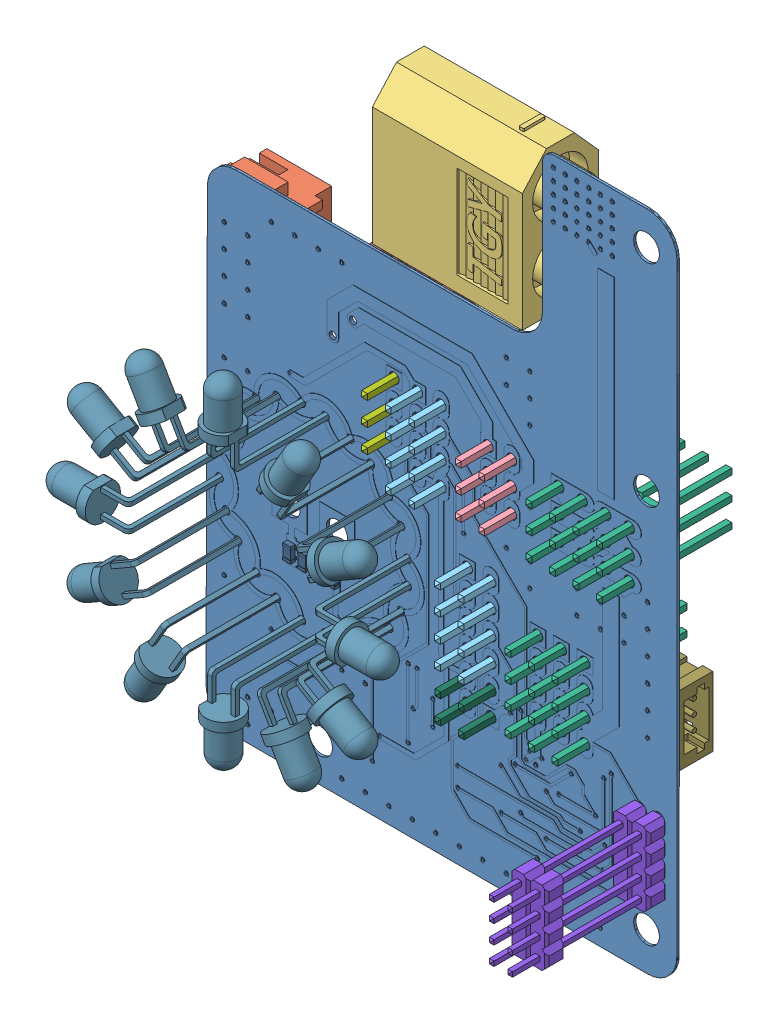
SolidWorks assembly pcb_distribution, configuration Default. Lengths in mm.
Overall size (57.82 71.9 27.2).
142 component instances, 19 part files, 0 mates.
Components (placement in the parent):
- Dip_distribution-1: Dip_distribution [Default] at origin size (51.25 71.9 0.34)
- S4B-XH-SM4-TB_distribution-1: S4B-XH-SM4-TB_distribution [Default] at (-4.2836 19.4855 0) x (0 1 0) z (-1 0 0) size (14.95 6 10)
- XT-60_distribution-1: XT-60_distribution [Default] at (18.1546 68.4711 30.4784) x (0 1 0) z (-1 0 0) size (16.3 8.2 21.2)
- 2x3_male_2.54x254_distribution-1: 2x3_male_2.54x254_distribution [Default] at (23.4683 11.0972 -0.0184) x (-1 0 0) z (0 -1 0) size (5.08 14.48 7.62)
- 2x4_male_2.54x254_distribution-1: 2x4_male_2.54x254_distribution [Default] at (13.354 17.4711 -0.0063) x (1 0 0) z (0 1 0) size (5.08 14.48 10.16)
- 2x4_male_2.54x254_distribution-2: 2x4_male_2.54x254_distribution [Default] at (21.2411 -3.9486 -0.0039) x (-1 0 0) z (0 -1 0) size (5.08 14.48 10.16)
- 3x4_male_2.54x254_distribution-3: 3x4_male_2.54x254_distribution [Default] at (26.2659 1.164 -0.0197) x (1 0 0) z (0 1 0) size (7.62 14.48 10.16)
- 3x4_male_2.54x254_distribution-6: 3x4_male_2.54x254_distribution [Default] at (28.5455 11.1175 -0.0174) x (0 1 0) z (-1 0 0) size (7.62 14.48 10.16)
- 1x3_male_2.54x254_distribution-1: 1x3_male_2.54x254_distribution [Default] at (10.8154 17.4747 -0.0262) x (0 -1 0) z (1 0 0) size (7.62 14.48 2.54)
- 2x4_male_2.0x2.0_distribution-1: 2x4_male_2.0x2.0_distribution [Default] at (39.2368 -9.9978 0.322) x (-1 0 0) z (0 1 0) size (4 18.21 8)
- 6444562_6444562_distribution-1: 6444562_6444562_distribution [Default] at (2.057 0 0.322)
- SOT 23_distribution-1: SOT 23_distribution [Default] at (20.6403 -14.1079 -0.55) x (-1 0 0) z (0 -1 0) size (3 1.1 2.5)
- SOT 23_distribution-2: SOT 23_distribution [Default] at (25.4006 -18.5273 -0.55) x (-1 0 0) z (0 -1 0) size (3 1.1 2.5)
- SOT 23_distribution-3: SOT 23_distribution [Default] at (15.8994 -18.4438 -0.55) x (-1 0 0) z (0 -1 0) size (3 1.1 2.5)
- SOT 23_distribution-4: SOT 23_distribution [Default] at (20.6481 -18.5304 -0.55) x (-1 0 0) z (0 -1 0) size (3 1.1 2.5)
- SOT 23_distribution-5: SOT 23_distribution [Default] at (15.873 -14.4885 -0.55) x (1 0 0) z (0 1 0) size (3 1.1 2.5)
- SOT 23_distribution-6: SOT 23_distribution [Default] at (25.3777 -14.0832 -0.55) x (-1 0 0) z (0 -1 0) size (3 1.1 2.5)
- Resistor 0603_distribution-1: Resistor 0603_distribution [Default] at (4.439 -4.231 0.352) x (0 1 0) z (1 0 0) size (1.6 0.51 0.86)
- Resistor 0603_distribution-2: Resistor 0603_distribution [Default] at (2.851 -4.231 0.352) x (0 1 0) z (1 0 0) size (1.6 0.51 0.86)
- Resistor 0603_distribution-3: Resistor 0603_distribution [Default] at (-0.324 -4.231 0.352) x (0 1 0) z (1 0 0) size (1.6 0.51 0.86)
- Resistor 0603_distribution-4: Resistor 0603_distribution [Default] at (1.264 -4.231 0.352) x (0 1 0) z (1 0 0) size (1.6 0.51 0.86)
- Resistor 0603_distribution-5: Resistor 0603_distribution [Default] at (12.065 -18.63 -0.03) x (0 -1 0) z (1 0 0) size (1.6 0.51 0.86)
- Resistor 0603_distribution-6: Resistor 0603_distribution [Default] at (9.208 -18.676 -0.03) x (0 1 0) z (-1 0 0) size (1.6 0.51 0.86)
- 4xRes_0402_distribution-1: 4xRes_0402_distribution [По умолчанию] at (31.8213 -10.0502 0) x (0 -1 0) z (1 0 0) size (2 0.37 1)
- 4xRes_0402_distribution-2: 4xRes_0402_distribution [По умолчанию] at (31.9306 -14.0825 0) x (0 1 0) z (-1 0 0) size (2 0.37 1)
- 4xRes_0402_distribution-3: 4xRes_0402_distribution [По умолчанию] at (31.9792 -18.2304 0) x (0 -1 0) z (1 0 0) size (2 0.37 1)
- S3B-ZR-SM4A-TF_distribution-1: S3B-ZR-SM4A-TF_distribution [Default] at (35.1671 -0.5265 0) x (0 -1 0) z (1 0 0) size (7.5 3.7 6.5)
- S3B-ZR-SM4A-TF_distribution-2: S3B-ZR-SM4A-TF_distribution [Default] at (-2.9698 -16.67 0) x (0 1 0) z (-1 0 0) size (7.5 3.7 6.5)
- S4B-ZR-SM4A-TF_distribution-1: S4B-ZR-SM4A-TF_distribution [Default] at (11.43 21.5177 0) x (1 0 0) z (0 1 0) size (9 3.7 6.5)
- LED DIP 3MM_distribution-1: LED DIP 3MM_distribution [Default] at (2.075 -11.8811 10.0396) x (0 0 1) z (0 -1 0) size (12.12 3.5 8.5)
- LED DIP 3MM_distribution-2: LED DIP 3MM_distribution [Default] at (12.389 5.9188 10.16) x (0 0 1) z (0.866025 0.5 0) size (12.12 3.5 8.5)
- LED DIP 3MM_distribution-3: LED DIP 3MM_distribution [Default] at (8.0206 10.3285 10.1335) x (0 0 1) z (0.5 0.866025 0) size (12.12 3.5 8.5)
- LED DIP 3MM_distribution-4: LED DIP 3MM_distribution [Default] at (8.0314 -10.3333 10.013) x (0 0 1) z (0.5 -0.866025 0) size (12.12 3.5 8.5)
- LED DIP 3MM_distribution-5: LED DIP 3MM_distribution [Default] at (-9.8416 -0.0229 10.1633) x (0 0 1) z (-1 0 0) size (12.12 3.5 8.5)
- LED DIP 3MM_distribution-6: LED DIP 3MM_distribution [Default] at (2.0728 11.943 10.1055) x (0 0 1) z (0 1 0) size (12.12 3.5 8.5)
- LED DIP 3MM_distribution-7: LED DIP 3MM_distribution [Default] at (12.4022 -5.9974 10.1382) x (0 0 1) z (0.866025 -0.5 0) size (12.12 3.5 8.5)
- LED DIP 3MM_distribution-8: LED DIP 3MM_distribution [Default] at (-8.2867 -5.9857 10.1382) x (0 0 1) z (-0.866025 -0.5 0) size (12.12 3.5 8.5)
- LED DIP 3MM_distribution-9: LED DIP 3MM_distribution [Default] at (-3.8923 10.3362 10.1121) x (0 0 1) z (-0.5 0.866025 0) size (12.12 3.5 8.5)
- LED DIP 3MM_distribution-10: LED DIP 3MM_distribution [Default] at (13.973 0.0173 10.0631) x (0 0 1) z (1 0 0) size (12.12 3.5 8.5)
- LED DIP 3MM_distribution-11: LED DIP 3MM_distribution [Default] at (-3.8857 -10.3081 10.1883) x (0 0 1) z (-0.5 -0.866025 0) size (12.12 3.5 8.5)
- LED DIP 3MM_distribution-12: LED DIP 3MM_distribution [Default] at (-8.2285 5.9806 10.1674) x (0 0 1) z (-0.866025 0.5 0) size (12.12 3.5 8.5)
- 2x2_male_2.54x254_distribution-1: 2x2_male_2.54x254_distribution [Default] at (21.251 -6.496 -0.0202) x (0 -1 0) z (1 0 0) size (5.08 14.48 5.08)
- Static_Via_Static_Via_distribution-1: Static_Via_Static_Via_distribution [Default] at (27.94 45.72 0.322)
- Static_Via_Static_Via_distribution-2: Static_Via_Static_Via_distribution [Default] at (29.21 45.72 0.322)
- Static_Via_Static_Via_distribution-3: Static_Via_Static_Via_distribution [Default] at (30.48 45.72 0.322)
- Static_Via_Static_Via_distribution-4: Static_Via_Static_Via_distribution [Default] at (31.75 45.72 0.322)
- Static_Via_Static_Via_distribution-5: Static_Via_Static_Via_distribution [Default] at (33.02 45.72 0.322)
- Static_Via_Static_Via_distribution-6: Static_Via_Static_Via_distribution [Default] at (34.29 45.72 0.322)
- Static_Via_Static_Via_distribution-7: Static_Via_Static_Via_distribution [Default] at (34.29 44.45 0.322)
- Static_Via_Static_Via_distribution-8: Static_Via_Static_Via_distribution [Default] at (33.02 44.45 0.322)
- Static_Via_Static_Via_distribution-9: Static_Via_Static_Via_distribution [Default] at (31.75 44.45 0.322)
- Static_Via_Static_Via_distribution-10: Static_Via_Static_Via_distribution [Default] at (30.48 44.45 0.322)
- Static_Via_Static_Via_distribution-11: Static_Via_Static_Via_distribution [Default] at (29.21 44.45 0.322)
- Static_Via_Static_Via_distribution-12: Static_Via_Static_Via_distribution [Default] at (27.94 44.45 0.322)
- Static_Via_Static_Via_distribution-13: Static_Via_Static_Via_distribution [Default] at (27.94 43.18 0.322)
- Static_Via_Static_Via_distribution-14: Static_Via_Static_Via_distribution [Default] at (29.21 43.18 0.322)
- Static_Via_Static_Via_distribution-15: Static_Via_Static_Via_distribution [Default] at (30.48 43.18 0.322)
- Static_Via_Static_Via_distribution-16: Static_Via_Static_Via_distribution [Default] at (31.75 43.18 0.322)
- Static_Via_Static_Via_distribution-17: Static_Via_Static_Via_distribution [Default] at (33.02 43.18 0.322)
- Static_Via_Static_Via_distribution-18: Static_Via_Static_Via_distribution [Default] at (34.29 43.18 0.322)
- Static_Via_Static_Via_distribution-19: Static_Via_Static_Via_distribution [Default] at (34.29 41.91 0.322)
- Static_Via_Static_Via_distribution-20: Static_Via_Static_Via_distribution [Default] at (33.02 41.91 0.322)
- Static_Via_Static_Via_distribution-21: Static_Via_Static_Via_distribution [Default] at (31.75 41.91 0.322)
- Static_Via_Static_Via_distribution-22: Static_Via_Static_Via_distribution [Default] at (30.48 41.91 0.322)
- Static_Via_Static_Via_distribution-23: Static_Via_Static_Via_distribution [Default] at (29.21 41.91 0.322)
- Static_Via_Static_Via_distribution-24: Static_Via_Static_Via_distribution [Default] at (27.94 41.91 0.322)
- Static_Via_Static_Via_distribution-25: Static_Via_Static_Via_distribution [Default] at (27.94 40.64 0.322)
- Static_Via_Static_Via_distribution-26: Static_Via_Static_Via_distribution [Default] at (29.21 40.64 0.322)
- Static_Via_Static_Via_distribution-27: Static_Via_Static_Via_distribution [Default] at (30.48 40.64 0.322)
- Static_Via_Static_Via_distribution-28: Static_Via_Static_Via_distribution [Default] at (31.75 40.64 0.322)
- Static_Via_Static_Via_distribution-29: Static_Via_Static_Via_distribution [Default] at (33.02 40.64 0.322)
- Static_Via_Static_Via_distribution-30: Static_Via_Static_Via_distribution [Default] at (34.29 40.64 0.322)
- Static_Via_Static_Via_distribution-31: Static_Via_Static_Via_distribution [Default] at (-7.62 -7.62 0.322)
- Static_Via_Static_Via_distribution-32: Static_Via_Static_Via_distribution [Default] at (-7.62 -10.16 0.322)
- Static_Via_Static_Via_distribution-33: Static_Via_Static_Via_distribution [Default] at (-5.08 -12.7 0.322)
- Static_Via_Static_Via_distribution-34: Static_Via_Static_Via_distribution [Default] at (-2.54 -12.7 0.322)
- Static_Via_Static_Via_distribution-35: Static_Via_Static_Via_distribution [Default] at (-5.08 -20.32 0.322)
- Static_Via_Static_Via_distribution-36: Static_Via_Static_Via_distribution [Default] at (-2.54 -20.32 0.322)
- Static_Via_Static_Via_distribution-37: Static_Via_Static_Via_distribution [Default] at (-5.08 -22.86 0.322)
- Static_Via_Static_Via_distribution-38: Static_Via_Static_Via_distribution [Default] at (-2.54 -22.86 0.322)
- Static_Via_Static_Via_distribution-39: Static_Via_Static_Via_distribution [Default] at (7.62 -12.7 0.322)
- Static_Via_Static_Via_distribution-40: Static_Via_Static_Via_distribution [Default] at (5.08 -12.7 0.322)
- Static_Via_Static_Via_distribution-41: Static_Via_Static_Via_distribution [Default] at (5.08 -17.78 0.322)
- Static_Via_Static_Via_distribution-42: Static_Via_Static_Via_distribution [Default] at (7.62 -17.78 0.322)
- Static_Via_Static_Via_distribution-43: Static_Via_Static_Via_distribution [Default] at (5.08 -22.86 0.322)
- Static_Via_Static_Via_distribution-44: Static_Via_Static_Via_distribution [Default] at (7.62 -22.86 0.322)
- Static_Via_Static_Via_distribution-45: Static_Via_Static_Via_distribution [Default] at (10.16 -22.86 0.322)
- Static_Via_Static_Via_distribution-46: Static_Via_Static_Via_distribution [Default] at (12.7 -22.86 0.322)
- Static_Via_Static_Via_distribution-47: Static_Via_Static_Via_distribution [Default] at (15.24 -22.86 0.322)
- Static_Via_Static_Via_distribution-48: Static_Via_Static_Via_distribution [Default] at (17.78 -22.86 0.322)
- Static_Via_Static_Via_distribution-49: Static_Via_Static_Via_distribution [Default] at (20.32 -22.86 0.322)
- Static_Via_Static_Via_distribution-50: Static_Via_Static_Via_distribution [Default] at (22.86 -22.86 0.322)
- Static_Via_Static_Via_distribution-51: Static_Via_Static_Via_distribution [Default] at (25.4 -22.86 0.322)
- Static_Via_Static_Via_distribution-52: Static_Via_Static_Via_distribution [Default] at (27.94 -22.86 0.322)
- Static_Via_Static_Via_distribution-53: Static_Via_Static_Via_distribution [Default] at (30.48 -22.86 0.322)
- Static_Via_Static_Via_distribution-54: Static_Via_Static_Via_distribution [Default] at (33.02 -22.86 0.322)
- Static_Via_Static_Via_distribution-55: Static_Via_Static_Via_distribution [Default] at (26.67 -10.16 0.322)
- Static_Via_Static_Via_distribution-56: Static_Via_Static_Via_distribution [Default] at (25.4 -10.16 0.322)
- Static_Via_Static_Via_distribution-57: Static_Via_Static_Via_distribution [Default] at (26.035 -11.112 0.322)
- Static_Via_Static_Via_distribution-58: Static_Via_Static_Via_distribution [Default] at (38.1 -2.54 0.322)
- Static_Via_Static_Via_distribution-59: Static_Via_Static_Via_distribution [Default] at (38.1 0 0.322)
- Static_Via_Static_Via_distribution-60: Static_Via_Static_Via_distribution [Default] at (38.1 2.54 0.322)
- Static_Via_Static_Via_distribution-61: Static_Via_Static_Via_distribution [Default] at (38.1 5.08 0.322)
- Static_Via_Static_Via_distribution-62: Static_Via_Static_Via_distribution [Default] at (38.1 7.62 0.322)
- Static_Via_Static_Via_distribution-63: Static_Via_Static_Via_distribution [Default] at (38.1 10.16 0.322)
- Static_Via_Static_Via_distribution-64: Static_Via_Static_Via_distribution [Default] at (35.56 7.62 0.322)
- Static_Via_Static_Via_distribution-65: Static_Via_Static_Via_distribution [Default] at (33.02 7.62 0.322)
- Static_Via_Static_Via_distribution-66: Static_Via_Static_Via_distribution [Default] at (30.48 7.62 0.322)
- Static_Via_Static_Via_distribution-67: Static_Via_Static_Via_distribution [Default] at (35.56 5.08 0.322)
- Static_Via_Static_Via_distribution-68: Static_Via_Static_Via_distribution [Default] at (33.02 5.08 0.322)
- Static_Via_Static_Via_distribution-69: Static_Via_Static_Via_distribution [Default] at (30.48 5.08 0.322)
- Static_Via_Static_Via_distribution-70: Static_Via_Static_Via_distribution [Default] at (25.4 7.62 0.322)
- Static_Via_Static_Via_distribution-71: Static_Via_Static_Via_distribution [Default] at (25.4 5.08 0.322)
- Static_Via_Static_Via_distribution-72: Static_Via_Static_Via_distribution [Default] at (22.86 7.62 0.322)
- Static_Via_Static_Via_distribution-73: Static_Via_Static_Via_distribution [Default] at (25.4 12.7 0.322)
- Static_Via_Static_Via_distribution-74: Static_Via_Static_Via_distribution [Default] at (25.4 20.32 0.322)
- Static_Via_Static_Via_distribution-75: Static_Via_Static_Via_distribution [Default] at (25.4 22.86 0.322)
- Static_Via_Static_Via_distribution-76: Static_Via_Static_Via_distribution [Default] at (25.4 25.4 0.322)
- Static_Via_Static_Via_distribution-77: Static_Via_Static_Via_distribution [Default] at (22.86 25.4 0.322)
- Static_Via_Static_Via_distribution-78: Static_Via_Static_Via_distribution [Default] at (22.86 22.86 0.322)
- Static_Via_Static_Via_distribution-79: Static_Via_Static_Via_distribution [Default] at (5.08 25.4 0.322)
- Static_Via_Static_Via_distribution-80: Static_Via_Static_Via_distribution [Default] at (2.54 25.4 0.322)
- Static_Via_Static_Via_distribution-81: Static_Via_Static_Via_distribution [Default] at (0 25.4 0.322)
- Static_Via_Static_Via_distribution-82: Static_Via_Static_Via_distribution [Default] at (-7.62 22.86 0.322)
- Static_Via_Static_Via_distribution-83: Static_Via_Static_Via_distribution [Default] at (-5.08 22.86 0.322)
- Static_Via_Static_Via_distribution-84: Static_Via_Static_Via_distribution [Default] at (-5.08 20.32 0.322)
- Static_Via_Static_Via_distribution-85: Static_Via_Static_Via_distribution [Default] at (-7.62 20.32 0.322)
- Static_Via_Static_Via_distribution-86: Static_Via_Static_Via_distribution [Default] at (-7.62 15.24 0.322)
- Static_Via_Static_Via_distribution-87: Static_Via_Static_Via_distribution [Default] at (-5.08 15.24 0.322)
- Static_Via_Static_Via_distribution-88: Static_Via_Static_Via_distribution [Default] at (-5.08 17.78 0.322)
- Static_Via_Static_Via_distribution-89: Static_Via_Static_Via_distribution [Default] at (-7.62 17.78 0.322)
- Static_Via_Static_Via_distribution-90: Static_Via_Static_Via_distribution [Default] at (-7.62 10.16 0.322)
- Static_Via_Static_Via_distribution-91: Static_Via_Static_Via_distribution [Default] at (-5.08 10.16 0.322)
- Static_Via_Static_Via_distribution-92: Static_Via_Static_Via_distribution [Default] at (-2.54 25.4 0.322)
- Hole_Hole_distribution-1: Hole_Hole_distribution [Default] at (37.998 -20.498 0.322)
- Hole_Hole_distribution-2: Hole_Hole_distribution [Default] at (37.998 20.498 0.322)
- Hole_Hole_distribution-3: Hole_Hole_distribution [Default] at (-37.998 20.498 0.322)
- Hole_Hole_distribution-4: Hole_Hole_distribution [Default] at (-37.998 -20.5 0.322)
- Hole_Hole_distribution-5: Hole_Hole_distribution [Default] at (37.998 43.294 0.322)
- Hole_Hole_distribution-6: Hole_Hole_distribution [Default] at (2.692 -20.498 0.322)
- Hole_1_Hole_1_distribution-1: Hole_1_Hole_1_distribution [Default] at (72.009 60.985 0.322)
- Hole_1_Hole_1_distribution-2: Hole_1_Hole_1_distribution [Default] at (72.009 -43.998 0.322)
